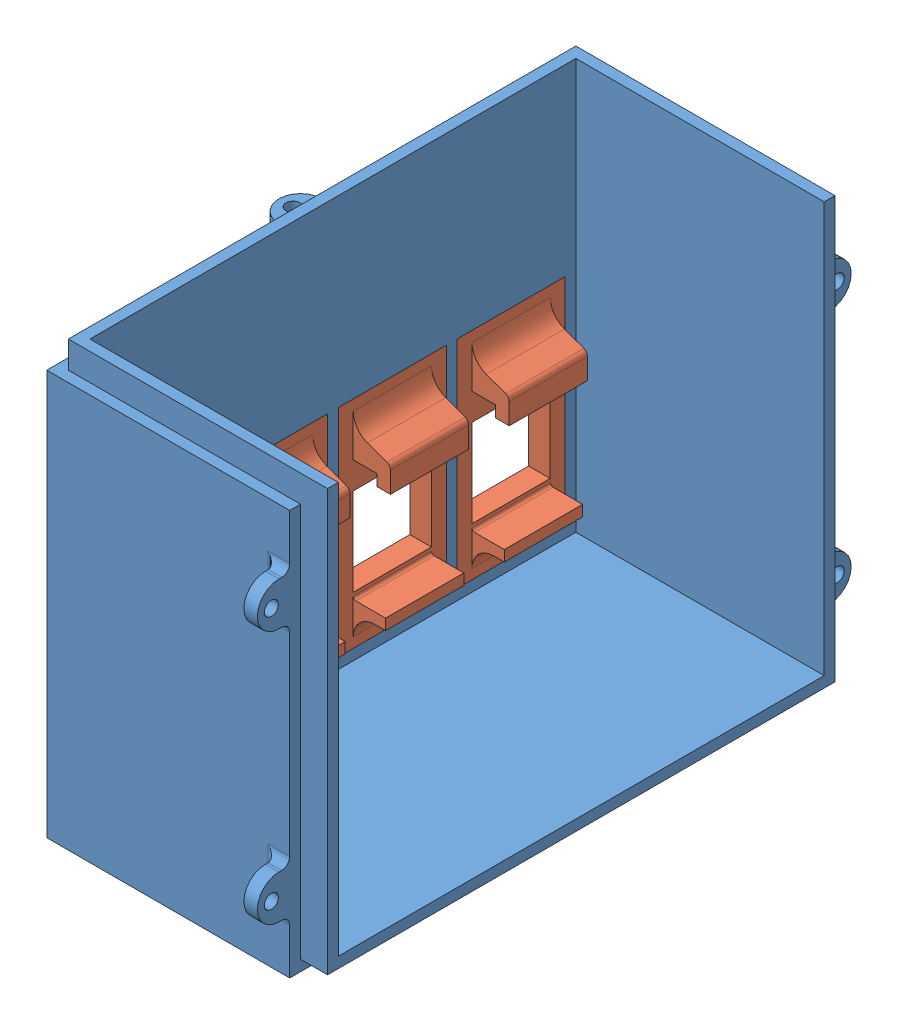
SolidWorks assembly rx0, configuration Default. Lengths in mm.
Overall size (56 80 110).
5 component instances, 2 part files, 4 mates.
Components (placement in the parent):
- 2rx-1: 2rx [Default] at (0.8552 39.4437 113.2293) size (56 80 110)
- rj45-1: rj45 [Default] at (-24.1448 65.4437 80.2293) x (0 1 0) z (0 0 -1) size (40 10.9 20)
- rj45-2: rj45 [Default] at (-24.1448 65.4437 102.2293) x (0 1 0) z (0 0 -1) size (40 10.9 20)
- rj45-3: rj45 [Default] at (-24.1448 65.4437 124.2293) x (0 1 0) z (0 0 -1) size (40 10.9 20)
- rj45-4: rj45 [Default] at (-24.1448 65.4437 146.2293) x (0 1 0) z (0 0 -1) size (40 10.9 20)
Mates (geometry in assembly coordinates):
- Coincident1: coincident: point of 2rx-1; point of rj45-1
- Coincident2: coincident: point of 2rx-1; point of rj45-2
- Coincident3: coincident: point of 2rx-1; point of rj45-3
- Coincident4: coincident: point of 2rx-1; point of rj45-4
